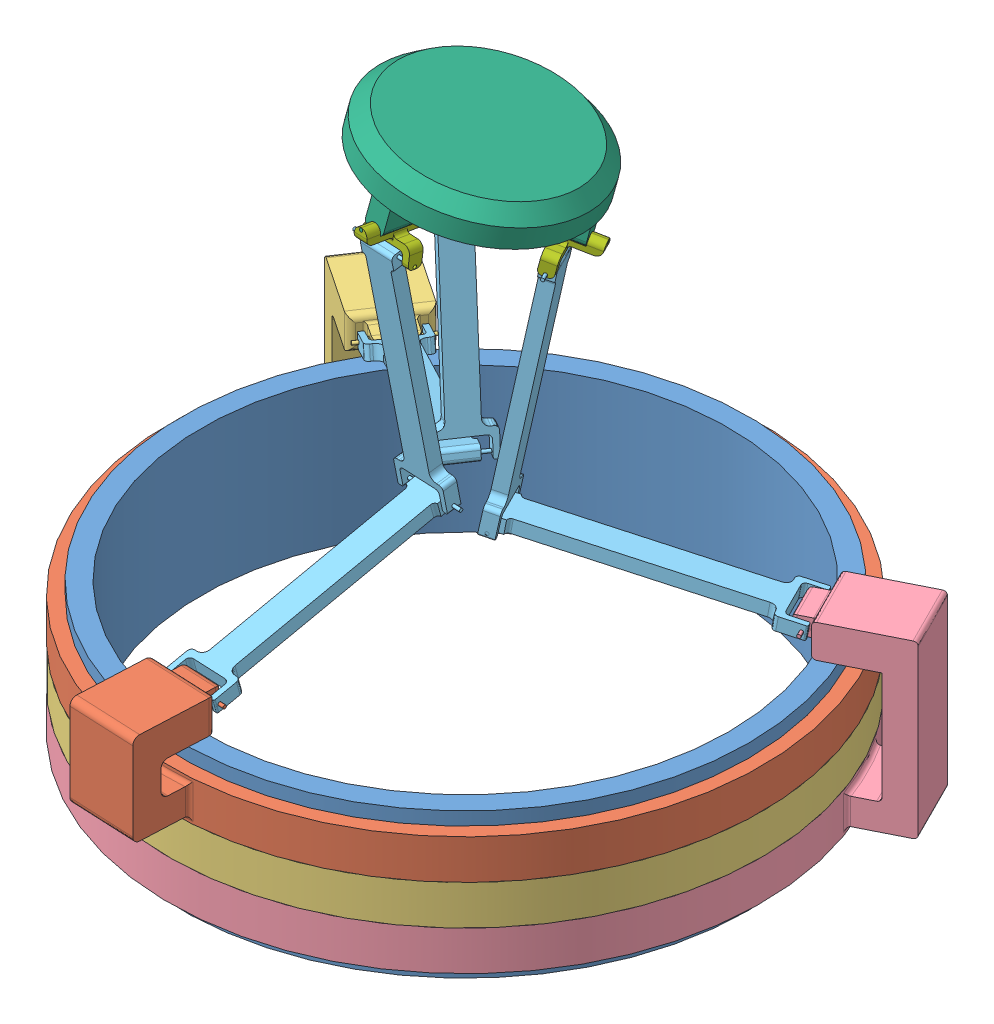
SolidWorks assembly Base_Assembled, configuration Default. Lengths in mm.
Overall size (682.44 431.39 646.46).
14 component instances, 7 part files, 34 mates.
Components (placement in the parent):
- Base-1: Base [Default] at (151.579 264.5648 307.4842) x (1 0 0) z (0 -1 0) size (430 430 110)
- ballbearingUp-1: ballbearingUp [Default] at (151.579 279.5648 307.4842) x (-0.998967 0 -0.045439) z (0.045439 0 -0.998967) size (450 75 489.62)
- ballbearingMid-1: ballbearingMid [Default] at (151.579 249.5648 307.4842) x (0.557042 0 -0.830485) z (0.830485 0 0.557042) size (450 105 489.62)
- ballbearingDown-1: ballbearingDown [Default] at (151.579 219.5648 307.4842) x (0.447597 0 0.894236) z (-0.894236 0 0.447597) size (450 135 489.62)
- LowerLink-2: LowerLink [Default] at (304.0111 349.5889 208.6016) x (0.447597 0 0.894236) z (0.88386 -0.15189 -0.442403) size (45.18 10 185)
- LowerLink-3: LowerLink [Default] at (-10.0089 351.0857 222.8139) x (0.557042 0 -0.830485) z (-0.805062 -0.245531 -0.53999) size (45.18 10 185)
- LowerLink-4: LowerLink [Default] at (123.7766 341.6291 485.3029) x (0.998967 0 0.045439) z (-0.043895 -0.258495 0.965015) size (45.18 10 185)
- LowerLink-8: LowerLink [Default] at (177.5177 386.8768 319.4371) x (-0.447597 0 -0.894236) z (-0.161645 -0.983527 0.080909) size (45.18 10 185)
- LowerLink-11: LowerLink [Default] at (146.7702 403.6207 276.8034) x (-0.557042 0 0.830485) z (0.142524 -0.985164 0.095597) size (45.18 10 185)
- LowerLink-12: LowerLink [Default] at (127.8059 405.9701 328.3855) x (0.998967 0 0.045439) z (0.008487 -0.982404 -0.186576) size (45.18 10 185)
- upperBase-1: upperBase [Default] at (163.8606 622.867 302.1831) x (-0.451268 -0.01835 -0.8922) z (-0.871757 0.222805 0.436345) size (150 50 155)
- spherical-4: spherical [Default] at (203.5139 568.1793 283.2824) x (0.871757 -0.222805 -0.436345) z (-0.447597 0 -0.894236) size (50 25 37.18)
- spherical-5: spherical [Default] at (109.9238 585.7168 277.0081) x (0.826688 -0.095511 0.554495) z (0.557042 0 -0.830485) size (50 25 37.18)
- spherical-6: spherical [Default] at (152.8051 587.4597 361.7375) x (-0.045069 0.127294 0.990841) z (0.998967 0 0.045439) size (50 25 37.18)
Mates (geometry in assembly coordinates):
- Concentric1: concentric anti-aligned: cylinder of Base-1 through (151.579 132.8078 307.4842) axis (0 -1 0) radius 200; cylinder of ballbearingUp-1 through (151.579 279.5648 307.4842) axis (0 1 0) radius 210
- Coincident1: coincident anti-aligned: plane of Base-1 through (-58.421 309.5648 307.4842) normal (0 -1 0); plane of ballbearingUp-1 through (151.579 309.5648 307.4842) normal (0 1 0)
- Concentric3: concentric anti-aligned: cylinder of Base-1 through (151.579 132.8078 307.4842) axis (0 -1 0) radius 210; cylinder of ballbearingMid-1 through (151.579 249.5648 307.4842) axis (0 1 0) radius 210
- Coincident2: coincident anti-aligned: plane of ballbearingUp-1 through (151.579 279.5648 307.4842) normal (0 -1 0); plane of ballbearingMid-1 through (151.579 279.5648 307.4842) normal (0 1 0)
- Concentric4: concentric anti-aligned: cylinder of Base-1 through (151.579 132.8078 307.4842) axis (0 -1 0) radius 210; cylinder of ballbearingDown-1 through (151.579 219.5648 307.4842) axis (0 1 0) radius 210
- Coincident3: coincident anti-aligned: plane of Base-1 through (-58.421 219.5648 307.4842) normal (0 1 0); plane of ballbearingDown-1 through (151.579 219.5648 307.4842) normal (0 -1 0)
- Tangent5: tangent aligned: cylinder of ballbearingMid-1 through (151.579 279.5648 307.4842) axis (0 -1 0) radius 225; cylinder of ballbearingDown-1 through (151.579 249.5648 307.4842) axis (0 -1 0) radius 225
- Coincident5: coincident anti-aligned: circle of ballbearingDown-1; plane of LowerLink-2 through (310.2208 348.8294 209.9665) normal (0.447597 0 0.894236)
- Concentric9: concentric anti-aligned: cylinder of ballbearingDown-1 through (316.791 342.0648 198.2908) axis (0.447597 0 0.894236) radius 1.25; cylinder of LowerLink-2 through (335.9885 342.0648 236.6446) axis (-0.447597 0 -0.894236) radius 1.25
- Concentric10: concentric aligned: cylinder of ballbearingDown-1 through (338.0037 342.0648 240.6708) axis (-0.447597 0 -0.894236) radius 1.25; cylinder of LowerLink-2 through (335.9885 342.0648 236.6446) axis (-0.447597 0 -0.894236) radius 1.25
- Coincident6: coincident anti-aligned: circle of ballbearingMid-1; plane of LowerLink-3 through (5.6795 349.8581 190.7231) normal (-0.557042 0 0.830485)
- Concentric11: concentric anti-aligned: cylinder of ballbearingMid-1 through (-24.9049 342.0648 217.6419) axis (0.557042 0 -0.830485) radius 1.25; cylinder of LowerLink-3 through (-0.7335 342.0648 181.6051) axis (-0.557042 0 0.830485) radius 1.25
- Concentric12: concentric aligned: cylinder of ballbearingMid-1 through (1.4947 342.0648 178.2832) axis (-0.557042 0 0.830485) radius 1.25; cylinder of LowerLink-3 through (-0.7335 342.0648 181.6051) axis (-0.557042 0 0.830485) radius 1.25
- Coincident7: coincident anti-aligned: circle of ballbearingUp-1; plane of LowerLink-4 through (158.9106 340.3366 491.7361) normal (-0.998967 0 -0.045439)
- Concentric13: concentric anti-aligned: cylinder of ballbearingUp-1 through (118.9734 342.0648 502.8175) axis (0.998967 0 0.045439) radius 1.25; cylinder of LowerLink-4 through (162.321 342.0648 504.7892) axis (-0.998967 0 -0.045439) radius 1.25
- Concentric14: concentric aligned: cylinder of ballbearingUp-1 through (166.3168 342.0648 504.9709) axis (-0.998967 0 -0.045439) radius 1.25; cylinder of LowerLink-4 through (162.321 342.0648 504.7892) axis (-0.998967 0 -0.045439) radius 1.25
- Concentric25: concentric anti-aligned: cylinder of LowerLink-3 through (144.9853 386.0149 275.8591) axis (-0.557042 0 0.830485) radius 1.25; cylinder of LowerLink-11 through (123.1604 386.0149 308.3974) axis (0.557042 0 -0.830485) radius 1.25
- Coincident12: coincident anti-aligned: plane of LowerLink-3 through (-6.0511 351.0857 216.9133) normal (-0.557042 0 0.830485); plane of LowerLink-11 through (127.7691 398.6949 306.6722) normal (0.557042 0 -0.830485)
- Concentric26: concentric aligned: cylinder of LowerLink-2 through (158.8509 369.253 278.0221) axis (0.447597 0 0.894236) radius 1.25; cylinder of LowerLink-8 through (161.5365 369.253 283.3875) axis (0.447597 0 0.894236) radius 1.25
- Coincident14: coincident anti-aligned: plane of LowerLink-2 through (307.1913 349.5889 214.9551) normal (-0.447597 0 -0.894236); plane of LowerLink-8 through (160.8691 381.9591 288.1946) normal (0.447597 0 0.894236)
- Concentric27: concentric aligned: cylinder of LowerLink-4 through (173.0701 388.3354 332.1831) axis (-0.998967 0 -0.045439) radius 1.25; cylinder of LowerLink-12 through (167.0763 388.3354 331.9104) axis (-0.998967 0 -0.045439) radius 1.25
- Coincident15: coincident anti-aligned: plane of LowerLink-4 through (156.0282 341.6291 486.7699) normal (0.998967 0 0.045439); plane of LowerLink-12 through (163.2018 401.0581 329.0607) normal (-0.998967 0 -0.045439)
- Concentric30: concentric anti-aligned: cylinder of upperBase-1 through (225.016 561.1815 272.5198) axis (-0.871757 0.222805 0.436345) radius 1.25; cylinder of spherical-4 through (181.4282 572.3218 294.3371) axis (0.871757 -0.222805 -0.436345) radius 1.25
- Coincident18: coincident anti-aligned: plane of upperBase-1 through (218.7291 558.6737 284.1575) normal (0.871757 -0.222805 -0.436345); plane of spherical-4 through (217.6328 558.988 281.8068) normal (-0.871757 0.222805 0.436345)
- Concentric31: concentric anti-aligned: cylinder of upperBase-1 through (151.6699 589.1895 386.6947) axis (0.045069 -0.127294 -0.990841) radius 1.25; cylinder of spherical-6 through (153.9234 582.8248 337.1527) axis (-0.045069 0.127294 0.990841) radius 1.25
- Coincident19: coincident anti-aligned: plane of upperBase-1 through (159.8733 577.8459 348.1554) normal (0.045069 -0.127294 -0.990841); plane of spherical-6 through (148.4516 579.5991 347.4106) normal (-0.045069 0.127294 0.990841)
- Concentric32: concentric aligned: cylinder of upperBase-1 through (89.1404 586.6468 263.0678) axis (0.826688 -0.095511 0.554495) radius 1.25; cylinder of spherical-5 through (89.1404 586.6468 263.0678) axis (0.826688 -0.095511 0.554495) radius 1.25
- Coincident20: coincident anti-aligned: plane of upperBase-1 through (100.4234 579.3023 263.0156) normal (-0.826688 0.095511 -0.554495); plane of spherical-5 through (94.2623 581.1769 272.5239) normal (0.826688 -0.095511 0.554495)
- Concentric33: concentric anti-aligned: cylinder of LowerLink-8 through (209.3975 545.3043 306.7175) axis (-0.447597 0 -0.894236) radius 1.25; cylinder of spherical-4 through (190.5179 545.3043 268.9987) axis (0.447597 0 0.894236) radius 1.25
- Coincident21: coincident anti-aligned: plane of LowerLink-8 through (174.3376 386.8768 313.0835) normal (0.447597 0 0.894236); plane of spherical-4 through (210.9669 552.4423 294.7493) normal (-0.447597 0 -0.894236)
- Concentric34: concentric aligned: cylinder of LowerLink-11 through (121.2032 562.3592 256.1686) axis (-0.557042 0 0.830485) radius 1.25; cylinder of spherical-5 through (118.418 562.3592 260.321) axis (-0.557042 0 0.830485) radius 1.25
- Coincident22: coincident anti-aligned: plane of LowerLink-11 through (142.8124 403.6207 282.704) normal (0.557042 0 -0.830485); plane of spherical-5 through (120.4376 570.3079 267.6963) normal (-0.557042 0 0.830485)
- Concentric35: concentric anti-aligned: cylinder of LowerLink-12 through (123.3159 564.1857 363.3861) axis (0.998967 0 0.045439) radius 1.25; cylinder of spherical-6 through (171.2402 564.1857 365.566) axis (-0.998967 0 -0.045439) radius 1.25
- Parallel1: parallel anti-aligned: plane of LowerLink-12 through (160.0576 405.9701 329.8524) normal (0.998967 0 0.045439); plane of spherical-6 through (166.069 573.2182 369.2166) normal (-0.998967 0 -0.045439)
